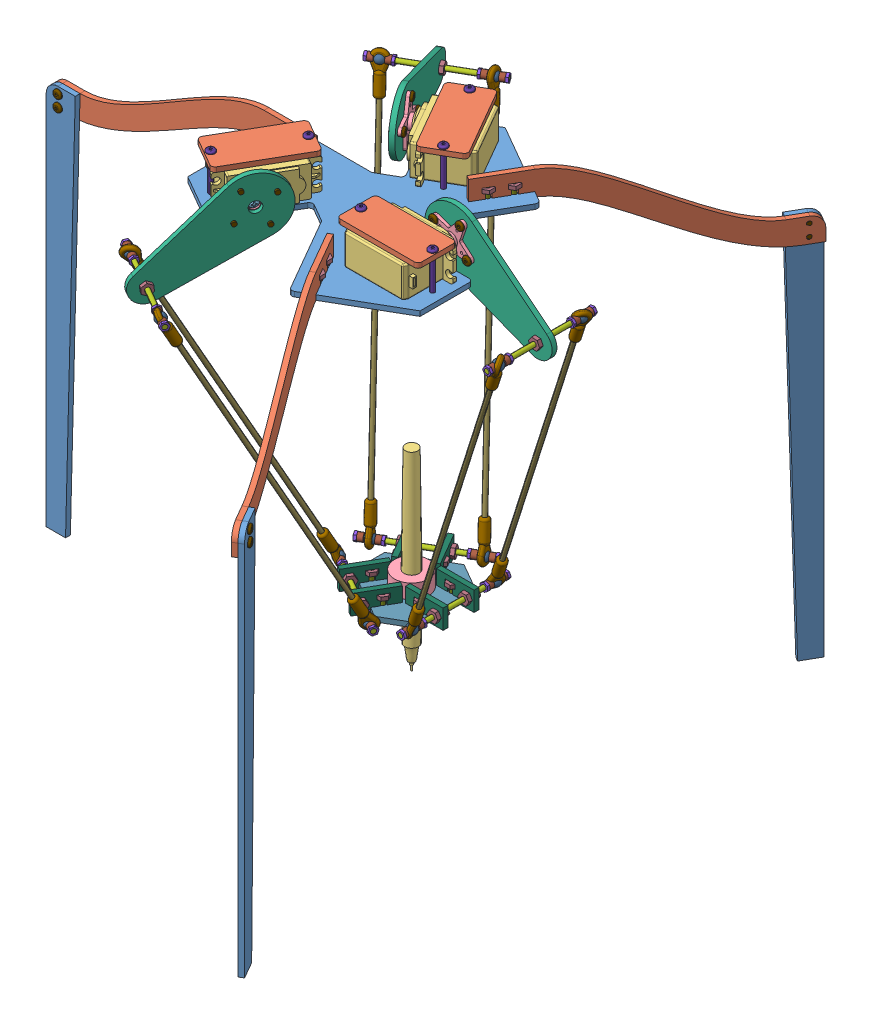
SolidWorks assembly robot, configuration Default. Lengths in mm.
Overall size (365.26 329.14 379.37).
210 component instances, 22 part files, 62 mates.
Components (placement in the parent):
- baseplate-1: baseplate [Default] at (-19.0722 -16.3081 15.1516) size (152.4 3.17 162.44)
- servo_cover-1: servo_cover [Default] at (26.6732 7.1869 43.9806) x (-1 0 0) z (0 1 0) size (53.34 25.4 3.17)
- servo_cover-2: servo_cover [Default] at (-16.9782 7.1869 -38.8796) x (0.5 0 0.866025) z (0 1 0) size (53.34 25.4 3.17)
- servo_cover-3: servo_cover [Default] at (-66.9115 7.1869 40.3538) x (0.5 0 -0.866025) z (0 1 0) size (53.34 25.4 3.17)
- servo_with_horn-2: servo_with_horn [Default] at (36.0362 17.1457 40.3908) x (0 1 0) z (-1 0 0) size (41.36 43.65 57.48) (flexible)
  - servo-1: servo [Default] at (-20.1188 -18.8299 -0.7716) size (20.32 41.27 53.29)
  - servohorn3-1: servohorn3 [Default] at (-20.1188 21.6577 -0.7716) x (-0.497836 0 -0.867271) z (0.867271 0 -0.497836) size (30.16 4.83 30.16)
  - #4 Screw-1: #4 Screw [90935A131] at (-20.1188 22.8928 -0.7716) x (1 0 0) z (0 1 0) size (5.56 5.56 8.28)
- arm-1: arm [Default] at (62.5908 -31.1625 3.6686) x (-0.865779 0.500426 0) z (0.500426 0.865779 0) size (152 113.14 262.73) (flexible)
  - upperarm-1: upperarm [Default] at (36.4291 9.905 11.5033) size (92.08 3.17 38.1)
  - elbow-1: elbow [Default] at (-23.4829 2.1195 2.2326) x (0.694665 0 -0.719334) z (0.719334 0 0.694665) size (27.1 71.7 23.49) (flexible)
    - elbow_rod-1: elbow_rod [Default] at (-9.1612 -25.5522 3.8591) size (2.95 69.85 2.95)
    - 4-40_nut-2: 4-40_nut [Default] at (-9.1612 42.7103 3.8591) x (-0.962597 0 -0.270938) z (0.270938 0 -0.962597) size (5.5 1.59 4.76)
    - balljoint-1: balljoint [Default] at (0.1328 32.669 -5.247) x (0.633314 -0.168787 -0.755264) z (-0.304454 0.842893 -0.443665) size (25.24 10.31 10.32) (flexible)
      - balljoint_joint-1: balljoint_joint [Default] at (-6.0674 0.1484 2.2064) size (25.24 5.95 10.32)
      - balljoint_ball-2: balljoint_ball [Default] at (-13.4478 0.1484 2.2064) x (-0.92173 -0.221131 -0.318613) z (-0.349176 0.830698 0.433609) size (6.35 5.63 6.35)
    - 4-40_spacer-1: 4-40_spacer [Default] at (-9.1612 39.5353 3.8591) x (0.693147 0 0.720796) z (-0.720796 0 0.693147) size (4.76 3.17 4.76)
    - 4-40_spacer-2: 4-40_spacer [Default] at (-9.1612 30.7353 3.8591) x (-0.319692 0 -0.947521) z (0.947521 0 -0.319692) size (4.76 3.17 4.76)
    - 4-40_spacer-4: 4-40_spacer [Default] at (-9.1612 -23.9647 3.8591) x (-0.98043 0 -0.196869) z (0.196869 0 -0.98043) size (4.76 3.17 4.76)
    - 4-40_spacer-5: 4-40_spacer [Default] at (-9.1612 -15.1646 3.8591) x (-0.915068 0 -0.403299) z (0.403299 0 -0.915068) size (4.76 3.17 4.76)
    - 4-40_nut-4: 4-40_nut [Default] at (-9.1612 -25.5522 3.8591) x (-0.98043 0 -0.196869) z (0.196869 0 -0.98043) size (5.5 1.59 4.76)
    - balljoint-2: balljoint [Default] at (0.3468 -18.3108 -5.8989) x (0.633314 -0.168787 -0.755264) z (-0.4896 -0.843183 -0.222111) size (25.24 10.26 10.32) (flexible)
      - balljoint_joint-1: balljoint_joint [Default] at (-6.0674 0.1484 2.2064) size (25.24 5.95 10.32)
      - balljoint_ball-2: balljoint_ball [Default] at (-13.4478 0.1484 2.2064) x (-0.6367 -0.596561 0.488598) z (0.752412 -0.619324 0.224308) size (6.35 5.63 6.35)
    - 4-40_nut-5: 4-40_nut [Default] at (-9.1612 29.1478 3.8591) x (0.327031 0 0.945013) z (-0.945013 0 0.327031) size (5.5 1.59 4.76)
    - 4-40_nut-6: 4-40_nut [Default] at (-9.1612 -11.9896 3.8591) x (0.998976 0 0.045234) z (-0.045234 0 0.998976) size (5.5 1.59 4.76)
  - lower_arm-1: lower_arm [Default] at (-51.4751 -1.0152 -219.9664) x (-0.230596 0.962712 -0.14146) z (0.967546 0.211415 -0.138414) size (2.79 228.6 2.79)
  - lower_arm-2: lower_arm [Default] at (-51.4751 -55.7152 -219.9664) x (-0.619276 -0.760264 0.196203) z (-0.778342 0.627303 -0.025956) size (2.79 228.6 2.79)
  - elbow-2: elbow [Default] at (-60.7209 -39.0108 -222.1485) x (-0.988334 0 0.152305) z (-0.152305 0 -0.988334) size (16.08 71.64 27.75) (flexible)
    - elbow_rod-1: elbow_rod [Default] at (-9.1612 -25.5522 3.8591) size (2.95 69.85 2.95)
    - 4-40_nut-2: 4-40_nut [Default] at (-9.1612 42.7103 3.8591) x (0.982806 0 -0.184641) z (0.184641 0 0.982806) size (5.5 1.59 4.76)
    - balljoint-1: balljoint [Default] at (-7.9824 41.1005 -8.9931) x (0.047152 0.168787 -0.984524) z (-0.310728 -0.934241 -0.175048) size (25.24 10.33 10.32) (flexible)
      - balljoint_joint-1: balljoint_joint [Default] at (-6.0674 0.1484 2.2064) size (25.24 5.95 10.32)
      - balljoint_ball-2: balljoint_ball [Default] at (-13.4478 0.1484 2.2064) x (-0.643697 -0.752934 0.136907) z (0.746435 -0.57826 0.329318) size (6.35 5.63 6.35)
    - 4-40_spacer-1: 4-40_spacer [Default] at (-9.1612 39.5353 3.8591) x (0.928598 0 0.371087) z (-0.371087 0 0.928598) size (4.76 3.17 4.76)
    - 4-40_spacer-2: 4-40_spacer [Default] at (-9.1612 30.7353 3.8591) x (-0.896981 0 0.442068) z (-0.442068 0 -0.896981) size (4.76 3.17 4.76)
    - 4-40_spacer-4: 4-40_spacer [Default] at (-9.1612 -23.9647 3.8591) x (-0.607719 0 -0.794152) z (0.794152 0 -0.607719) size (4.76 3.17 4.76)
    - 4-40_spacer-5: 4-40_spacer [Default] at (-9.1612 -15.1646 3.8591) x (0.496208 0 -0.868204) z (0.868204 0 0.496208) size (4.76 3.17 4.76)
    - 4-40_nut-4: 4-40_nut [Default] at (-9.1612 -25.5522 3.8591) x (0.965897 0 -0.258927) z (0.258927 0 0.965897) size (5.5 1.59 4.76)
    - balljoint-2: balljoint [Default] at (-7.7302 -17.7465 -9.692) x (0.047152 0.168787 -0.984524) z (-0.297051 0.943399 0.14751) size (25.24 9.83 10.32) (flexible)
      - balljoint_joint-1: balljoint_joint [Default] at (-6.0674 0.1484 2.2064) size (25.24 5.95 10.32)
      - balljoint_ball-2: balljoint_ball [Default] at (-13.4478 0.1484 2.2064) x (-0.644652 0.692059 0.324773) z (0.74561 0.662982 0.067237) size (6.35 5.63 6.35)
    - 4-40_nut-5: 4-40_nut [Default] at (-9.1612 29.1478 3.8591) x (0.327031 0 0.945013) z (-0.945013 0 0.327031) size (5.5 1.59 4.76)
    - 4-40_nut-6: 4-40_nut [Default] at (-9.1612 -11.9896 3.8591) x (0.998976 0 0.045234) z (-0.045234 0 0.998976) size (5.5 1.59 4.76)
  - 4-40_nut_wide-1: 4-40_nut_wide [Default] at (-27.0709 15.4613 11.5033) x (-0.82771 0 -0.561156) z (-0.561156 0 0.82771) size (7.33 2.38 6.35)
  - 4-40_nut_wide-2: 4-40_nut_wide [Default] at (-27.0709 7.5238 11.5033) x (0.999854 0 0.017072) z (-0.017072 0 0.999854) size (7.33 2.38 6.35)
- servo_with_horn-5: servo_with_horn [Default] at (-68.4841 17.1457 50.2573) x (0 1 0) z (0.5 0 -0.866025) size (41.99 43.65 57.8) (flexible)
  - servo-1: servo [Default] at (-20.1188 -18.8299 -0.7716) size (20.32 41.27 53.29)
  - servohorn3-1: servohorn3 [Default] at (-20.1188 21.6577 -0.7716) x (0.827646 0 -0.56125) z (0.56125 0 0.827646) size (30.16 4.83 30.16)
  - #4 Screw-1: #4 Screw [90935A131] at (-20.1188 22.8928 -0.7716) x (1 0 0) z (0 1 0) size (5.56 5.56 8.28)
- servo_with_horn-6: servo_with_horn [Default] at (-24.7686 17.1457 -45.1932) x (0 1 0) z (0.5 0 0.866025) size (36.75 43.65 55.18) (flexible)
  - servo-1: servo [Default] at (-20.1188 -18.8299 -0.7716) size (20.32 41.27 53.29)
  - servohorn3-1: servohorn3 [Default] at (-20.1188 21.6577 -0.7716) x (-0.191432 0 -0.981506) z (0.981506 0 -0.191432) size (30.16 4.83 30.16)
  - #4 Screw-1: #4 Screw [90935A131] at (-20.1188 22.8928 -0.7716) x (1 0 0) z (0 1 0) size (5.56 5.56 8.28)
- arm-4: arm [Default] at (-48.8699 -33.0103 89.7287) x (0.412983 0.563721 -0.715307) z (-0.281861 0.825965 0.488197) size (152.59 104.09 264.5) (flexible)
  - upperarm-1: upperarm [Default] at (36.4291 9.905 11.5033) size (92.08 3.17 38.1)
  - elbow-1: elbow [Default] at (-26.9301 2.1195 1.5635) x (0.401226 0 -0.915979) z (0.915979 0 0.401226) size (27.18 70.02 18.21) (flexible)
    - elbow_rod-1: elbow_rod [Default] at (-9.1612 -25.5522 3.8591) size (2.95 69.85 2.95)
    - 4-40_nut-2: 4-40_nut [Default] at (-9.1612 42.7103 3.8591) x (0.771228 0 0.636559) z (-0.636559 0 0.771228) size (5.5 1.59 4.76)
    - balljoint-1: balljoint [Default] at (3.4055 37.7799 -1.3074) x (0.848208 0.135879 -0.511938) z (-0.518583 0.409713 -0.750471) size (25.24 9.15 10.32) (flexible)
      - balljoint_joint-1: balljoint_joint [Default] at (-6.0674 0.1484 2.2064) size (25.24 5.95 10.32)
      - balljoint_ball-2: balljoint_ball [Default] at (-13.4478 0.1484 2.2064) x (0.953113 0.231885 0.194432) z (0.270392 -0.364083 -0.891253) size (6.35 5.63 6.35)
    - 4-40_spacer-1: 4-40_spacer [Default] at (-9.1612 39.5353 3.8591) x (-0.343072 0 -0.939309) z (0.939309 0 -0.343072) size (4.76 3.17 4.76)
    - 4-40_spacer-2: 4-40_spacer [Default] at (-9.1612 30.7353 3.8591) x (-0.090134 0 0.99593) z (-0.99593 0 -0.090134) size (4.76 3.17 4.76)
    - 4-40_spacer-4: 4-40_spacer [Default] at (-9.1612 -23.9647 3.8591) x (0.817451 0 0.575998) z (-0.575998 0 0.817451) size (4.76 3.17 4.76)
    - 4-40_spacer-5: 4-40_spacer [Default] at (-9.1612 -15.1646 3.8591) x (0.6743 0 0.738458) z (-0.738458 0 0.6743) size (4.76 3.17 4.76)
    - 4-40_nut-4: 4-40_nut [Default] at (-9.1612 -25.5522 3.8591) x (0.817451 0 0.575998) z (-0.575998 0 0.817451) size (5.5 1.59 4.76)
    - balljoint-2: balljoint [Default] at (2.47 -18.3399 -3.2343) x (0.848208 0.135879 -0.511938) z (-0.066506 0.986207 0.151568) size (25.24 9.61 10.32) (flexible)
      - balljoint_joint-1: balljoint_joint [Default] at (-6.0674 0.1484 2.2064) size (25.24 5.95 10.32)
      - balljoint_ball-2: balljoint_ball [Default] at (-13.4478 0.1484 2.2064) x (0.572901 -0.819625 -0.000384) z (-0.808283 -0.565051 0.165517) size (6.35 5.63 6.35)
    - 4-40_nut-5: 4-40_nut [Default] at (-9.1612 29.1478 3.8591) x (0.327031 0 0.945013) z (-0.945013 0 0.327031) size (5.5 1.59 4.76)
    - 4-40_nut-6: 4-40_nut [Default] at (-9.1612 -11.9896 3.8591) x (0.998976 0 0.045234) z (-0.045234 0 0.998976) size (5.5 1.59 4.76)
  - lower_arm-1: lower_arm [Default] at (-57.439 70.9288 -220.4679) x (-0.737442 -0.675404 0.003118) z (-0.663055 0.724822 0.187061) size (2.79 228.6 2.79)
  - lower_arm-2: lower_arm [Default] at (-57.439 16.2288 -220.4679) x (-0.086585 -0.988324 -0.125371) z (-0.987909 0.068933 0.138865) size (2.79 228.6 2.79)
  - elbow-2: elbow [Default] at (-49.5976 35.2306 -232.4779) x (0.996584 0 -0.082591) z (0.082591 0 0.996584) size (17.13 70.14 27.46) (flexible)
    - elbow_rod-1: elbow_rod [Default] at (-9.1612 -25.5522 3.8591) size (2.95 69.85 2.95)
    - 4-40_nut-2: 4-40_nut [Default] at (-9.1612 42.7103 3.8591) x (0.982333 0 -0.187143) z (0.187143 0 0.982333) size (5.5 1.59 4.76)
    - balljoint-1: balljoint [Default] at (-7.5187 36.8504 17.3875) x (0.04703 -0.135879 0.989609) z (-0.396092 -0.912025 -0.106403) size (25.24 10.51 10.32) (flexible)
      - balljoint_joint-1: balljoint_joint [Default] at (-6.0674 0.1484 2.2064) size (25.24 5.95 10.32)
      - balljoint_ball-2: balljoint_ball [Default] at (-13.4478 0.1484 2.2064) x (0.574702 0.780639 0.245602) z (-0.807003 0.490771 0.328466) size (6.35 5.63 6.35)
    - 4-40_spacer-1: 4-40_spacer [Default] at (-9.1612 39.5353 3.8591) x (0.92954 0 0.368721) z (-0.368721 0 0.92954) size (4.76 3.17 4.76)
    - 4-40_spacer-2: 4-40_spacer [Default] at (-9.1612 30.7353 3.8591) x (-0.895853 0 0.444351) z (-0.444351 0 -0.895853) size (4.76 3.17 4.76)
    - 4-40_spacer-4: 4-40_spacer [Default] at (-9.1612 -23.9647 3.8591) x (-0.609739 0 -0.792602) z (0.792602 0 -0.609739) size (4.76 3.17 4.76)
    - 4-40_spacer-5: 4-40_spacer [Default] at (-9.1612 -15.1646 3.8591) x (0.493996 0 -0.869464) z (0.869464 0 0.493996) size (4.76 3.17 4.76)
    - 4-40_nut-4: 4-40_nut [Default] at (-9.1612 -25.5522 3.8591) x (0.965234 0 -0.261386) z (0.261386 0 0.965234) size (5.5 1.59 4.76)
    - balljoint-2: balljoint [Default] at (-10.424 -18.6911 17.4101) x (0.04703 -0.135879 0.989609) z (0.889518 -0.445051 -0.103381) size (25.24 9.07 10.57) (flexible)
      - balljoint_joint-1: balljoint_joint [Default] at (-6.0674 0.1484 2.2064) size (25.24 5.95 10.32)
      - balljoint_ball-2: balljoint_ball [Default] at (-13.4478 0.1484 2.2064) x (0.575735 0.295033 -0.762552) z (-0.806267 0.359846 -0.469515) size (6.35 5.63 6.35)
    - 4-40_nut-5: 4-40_nut [Default] at (-9.1612 29.1478 3.8591) x (0.327031 0 0.945013) z (-0.945013 0 0.327031) size (5.5 1.59 4.76)
    - 4-40_nut-6: 4-40_nut [Default] at (-9.1612 -11.9896 3.8591) x (0.998976 0 0.045234) z (-0.045234 0 0.998976) size (5.5 1.59 4.76)
  - 4-40_nut_wide-1: 4-40_nut_wide [Default] at (-27.0709 15.4613 11.5033) x (-0.830576 0 -0.556905) z (-0.556905 0 0.830576) size (7.33 2.38 6.35)
  - 4-40_nut_wide-2: 4-40_nut_wide [Default] at (-27.0709 7.5238 11.5033) x (0.999929 0 0.011945) z (-0.011945 0 0.999929) size (7.33 2.38 6.35)
- arm-5: arm [Default] at (-73.706 -21.3376 -56.511) x (0.490465 0.194365 0.84951) z (-0.097182 0.980929 -0.168325) size (152.71 78.88 264.12) (flexible)
  - upperarm-1: upperarm [Default] at (36.4291 9.905 11.5033) size (92.08 3.17 38.1)
  - elbow-1: elbow [Default] at (-34.7249 2.1195 5.1601) x (-0.461858 0 -0.886954) z (0.886954 0 -0.461858) size (26.53 69.85 25.43) (flexible)
    - elbow_rod-1: elbow_rod [Default] at (-9.1612 -25.5522 3.8591) size (2.95 69.85 2.95)
    - 4-40_nut-2: 4-40_nut [Default] at (-9.1612 42.7103 3.8591) x (0.901206 0 0.433391) z (-0.433391 0 0.901206) size (5.5 1.59 4.76)
    - balljoint-1: balljoint [Default] at (3.7419 37.6048 8.1563) x (0.885824 0.032796 0.462862) z (-0.438882 -0.264659 0.858684) size (25.24 7.66 10.32) (flexible)
      - balljoint_joint-1: balljoint_joint [Default] at (-6.0674 0.1484 2.2064) size (25.24 5.95 10.32)
      - balljoint_ball-2: balljoint_ball [Default] at (-13.4478 0.1484 2.2064) x (0.028042 -0.265585 -0.96368) z (0.999069 -0.024184 0.035736) size (6.35 5.63 6.35)
    - 4-40_spacer-1: 4-40_spacer [Default] at (-9.1612 39.5353 3.8591) x (-0.55799 0 -0.829847) z (0.829847 0 -0.55799) size (4.76 3.17 4.76)
    - 4-40_spacer-2: 4-40_spacer [Default] at (-9.1612 30.7353 3.8591) x (0.150941 0 0.988543) z (-0.988543 0 0.150941) size (4.76 3.17 4.76)
    - 4-40_spacer-4: 4-40_spacer [Default] at (-9.1612 -23.9647 3.8591) x (0.931585 0 0.363524) z (-0.363524 0 0.931585) size (4.76 3.17 4.76)
    - 4-40_spacer-5: 4-40_spacer [Default] at (-9.1612 -15.1646 3.8591) x (0.831495 0 0.555533) z (-0.555533 0 0.831495) size (4.76 3.17 4.76)
    - 4-40_nut-4: 4-40_nut [Default] at (-9.1612 -25.5522 3.8591) x (0.931585 0 0.363524) z (-0.363524 0 0.931585) size (5.5 1.59 4.76)
    - balljoint-2: balljoint [Default] at (2.6927 -19.7305 10.3509) x (0.885824 0.032796 0.462862) z (-0.004709 0.998083 -0.061709) size (25.24 9.01 10.32) (flexible)
      - balljoint_joint-1: balljoint_joint [Default] at (-6.0674 0.1484 2.2064) size (25.24 5.95 10.32)
      - balljoint_ball-2: balljoint_ball [Default] at (-13.4478 0.1484 2.2064) x (0.951176 0.308281 -0.015044) z (0.306901 -0.949846 -0.060032) size (6.35 5.63 6.35)
    - 4-40_nut-5: 4-40_nut [Default] at (-9.1612 29.1478 3.8591) x (0.327031 0 0.945013) z (-0.945013 0 0.327031) size (5.5 1.59 4.76)
    - 4-40_nut-6: 4-40_nut [Default] at (-9.1612 -11.9896 3.8591) x (0.998976 0 0.045234) z (-0.045234 0 0.998976) size (5.5 1.59 4.76)
  - lower_arm-1: lower_arm [Default] at (-26.7375 46.5868 -224.51) x (-0.946031 0.323943 0.009293) z (0.324073 0.945508 0.031484) size (2.79 228.6 2.79)
  - lower_arm-2: lower_arm [Default] at (-26.7375 -8.1131 -224.51) x (-0.912676 -0.40842 -0.014691) z (-0.408681 0.912205 0.029356) size (2.79 228.6 2.79)
  - elbow-2: elbow [Default] at (-36.6397 10.1113 -231.3019) x (-0.948064 0 -0.318079) z (0.318079 0 -0.948064) size (13.16 69.85 26.08) (flexible)
    - elbow_rod-1: elbow_rod [Default] at (-9.1612 -25.5522 3.8591) size (2.95 69.85 2.95)
    - 4-40_nut-2: 4-40_nut [Default] at (-9.1612 42.7103 3.8591) x (0.171643 0 0.985159) z (-0.985159 0 0.171643) size (5.5 1.59 4.76)
    - balljoint-1: balljoint [Default] at (-15.4085 35.6062 -8.2015) x (-0.316569 -0.032796 -0.948002) z (0.918033 0.240947 -0.314897) size (25.24 7.7 10.32) (flexible)
      - balljoint_joint-1: balljoint_joint [Default] at (-6.0674 0.1484 2.2064) size (25.24 5.95 10.32)
      - balljoint_ball-2: balljoint_ball [Default] at (-13.4478 0.1484 2.2064) x (0.946092 0.107855 -0.305415) z (0.322235 -0.217942 0.921231) size (6.35 5.63 6.35)
    - 4-40_spacer-1: 4-40_spacer [Default] at (-9.1612 39.5353 3.8591) x (-0.383321 0 0.923615) z (-0.923615 0 -0.383321) size (4.76 3.17 4.76)
    - 4-40_spacer-2: 4-40_spacer [Default] at (-9.1612 30.7353 3.8591) x (-0.430181 0 -0.902743) z (0.902743 0 -0.430181) size (4.76 3.17 4.76)
    - 4-40_spacer-4: 4-40_spacer [Default] at (-9.1612 -23.9647 3.8591) x (0.80211 0 -0.597176) z (0.597176 0 0.80211) size (4.76 3.17 4.76)
    - 4-40_spacer-5: 4-40_spacer [Default] at (-9.1612 -15.1646 3.8591) x (0.861573 0 0.507633) z (-0.507633 0 0.861573) size (4.76 3.17 4.76)
    - 4-40_nut-4: 4-40_nut [Default] at (-9.1612 -25.5522 3.8591) x (0.246146 0 0.969233) z (-0.969233 0 0.246146) size (5.5 1.59 4.76)
    - balljoint-2: balljoint [Default] at (-15.5045 -18.625 -8.1856) x (-0.316569 -0.032796 -0.948002) z (0.947902 0.026543 -0.317453) size (25.24 6 10.32) (flexible)
      - balljoint_joint-1: balljoint_joint [Default] at (-6.0674 0.1484 2.2064) size (25.24 5.95 10.32)
      - balljoint_ball-2: balljoint_ball [Default] at (-13.4478 0.1484 2.2064) x (0.945678 0.039615 -0.322681) z (0.323445 -0.014518 0.946135) size (6.35 5.63 6.35)
    - 4-40_nut-5: 4-40_nut [Default] at (-9.1612 29.1478 3.8591) x (0.327031 0 0.945013) z (-0.945013 0 0.327031) size (5.5 1.59 4.76)
    - 4-40_nut-6: 4-40_nut [Default] at (-9.1612 -11.9896 3.8591) x (0.998976 0 0.045234) z (-0.045234 0 0.998976) size (5.5 1.59 4.76)
  - 4-40_nut_wide-1: 4-40_nut_wide [Default] at (-27.0709 15.4613 11.5033) x (-0.802812 0 -0.596233) z (-0.596233 0 0.802812) size (7.33 2.38 6.35)
  - 4-40_nut_wide-2: 4-40_nut_wide [Default] at (-27.0709 7.5238 11.5033) x (0.998195 0 0.060055) z (-0.060055 0 0.998195) size (7.33 2.38 6.35)
- hand-1: hand [Default] at (-35.5542 -256.4649 -27.669) size (60.32 14.2 67.85)
  - hand_base-1: hand_base [Default] at (1.9794 -4.0388 1.6994) size (50.8 3.17 58.66)
  - wrist_connector-2: wrist_connector [Default] at (29.61 2.3112 11.8594) x (0 0 -1) z (1 0 0) size (3.17 12.7 24.77)
  - wrist_connector-6: wrist_connector [Default] at (-20.6348 2.3112 20.5483) x (0.866025 0 0.5) z (-0.5 0 0.866025) size (3.17 12.7 24.77)
  - wrist_connector-7: wrist_connector [Default] at (-3.0372 2.3112 -27.3094) x (-0.866025 0 0.5) z (-0.5 0 -0.866025) size (3.17 12.7 24.77)
  - 4-40_38_screw-3: 4-40_38_screw [Default] at (18.4975 5.4862 11.8594) x (-0.241512 0 0.970398) z (0.970398 0 0.241512) size (5.41 11.02 5.41)
  - 4-40_nut_wide-1: 4-40_nut_wide [Default] at (18.4975 2.8192 11.8594) size (7.33 2.38 6.35)
  - 4-40_nut_wide-4: 4-40_nut_wide [Default] at (-15.0785 2.8192 10.9246) x (-0.5 0 0.866025) z (-0.866025 0 -0.5) size (7.33 2.38 6.35)
  - 4-40_nut_wide-5: 4-40_nut_wide [Default] at (2.5191 2.8192 -17.6857) x (-0.5 0 -0.866025) z (0.866025 0 -0.5) size (7.33 2.38 6.35)
  - 4-40_38_screw-4: 4-40_38_screw [Default] at (-15.0785 5.4862 10.9246) x (-0.719633 0 -0.694354) z (-0.694354 0 0.719633) size (5.41 11.02 5.41)
  - 4-40_38_screw-5: 4-40_38_screw [Default] at (2.5191 5.4862 -17.6857) x (0.961145 0 -0.276044) z (-0.276044 0 -0.961145) size (5.41 11.02 5.41)
  - 4-40_38_screw-8: 4-40_38_screw [Default] at (18.4975 5.4862 -8.4606) x (-0.241512 0 0.970398) z (0.970398 0 0.241512) size (5.41 11.02 5.41)
  - 4-40_nut_wide-8: 4-40_nut_wide [Default] at (18.4975 2.8192 -8.4606) size (7.33 2.38 6.35)
  - wrist_connector-11: wrist_connector [Default] at (29.61 2.3112 -8.4606) x (0 0 -1) z (1 0 0) size (3.17 12.7 24.77)
  - wrist_connector-12: wrist_connector [Default] at (-3.0372 2.3112 30.7083) x (0.866025 0 0.5) z (-0.5 0 0.866025) size (3.17 12.7 24.77)
  - wrist_connector-13: wrist_connector [Default] at (-20.6348 2.3112 -17.1494) x (-0.866025 0 0.5) z (-0.5 0 -0.866025) size (3.17 12.7 24.77)
  - 4-40_nut_wide-9: 4-40_nut_wide [Default] at (2.5191 2.8192 21.0846) x (-0.5 0 0.866025) z (-0.866025 0 -0.5) size (7.33 2.38 6.35)
  - 4-40_nut_wide-10: 4-40_nut_wide [Default] at (-15.0785 2.8192 -7.5257) x (-0.5 0 -0.866025) z (0.866025 0 -0.5) size (7.33 2.38 6.35)
  - 4-40_38_screw-9: 4-40_38_screw [Default] at (2.5191 5.4862 21.0846) x (-0.719633 0 -0.694354) z (-0.694354 0 0.719633) size (5.41 11.02 5.41)
  - 4-40_38_screw-10: 4-40_38_screw [Default] at (-15.0785 5.4862 -7.5257) x (0.961145 0 -0.276044) z (-0.276044 0 -0.961145) size (5.41 11.02 5.41)
- 4-40_125_screw-1: 4-40_125_screw [Default] at (50.1682 -21.3881 43.9806) size (5.41 33.25 5.41)
- 4-40_125_screw-6: 4-40_125_screw [Default] at (-78.659 -21.3881 60.7011) x (-0.5 0 0.866025) z (-0.866025 0 -0.5) size (5.41 33.25 5.41)
- 4-40_125_screw-5: 4-40_125_screw [Default] at (-28.7257 -21.3881 -59.2268) x (-0.5 0 -0.866025) z (0.866025 0 -0.5) size (5.41 33.25 5.41)
- 4-40_125_screw-2: 4-40_125_screw [Default] at (3.1782 -21.3881 43.9806) size (5.41 33.25 5.41)
- 4-40_125_screw-4: 4-40_125_screw [Default] at (-55.164 -21.3881 20.0065) x (-0.5 0 0.866025) z (-0.866025 0 -0.5) size (5.41 33.25 5.41)
- 4-40_125_screw-3: 4-40_125_screw [Default] at (-5.2307 -21.3881 -18.5323) x (-0.5 0 -0.866025) z (0.866025 0 -0.5) size (5.41 33.25 5.41)
- 4-40_nut_wide-17: 4-40_nut_wide [Default] at (-5.9442 -254.1537 -17.3971) x (0.5 0.866025 0) z (-0.866025 0.5 0) size (7.33 2.38 6.35)
- 4-40_nut_wide-18: 4-40_nut_wide [Default] at (-5.9442 -254.1537 -11.8408) x (0.5 0.866025 0) z (-0.866025 0.5 0) size (7.33 2.38 6.35)
- 4-40_14_screw-1: 4-40_14_screw [Default] at (43.1632 8.0223 12.383) x (-0.533794 -0.845615 0) z (-0.845615 0.533794 0) size (5.41 7.85 5.41)
- 4-40_14_screw-5: 4-40_14_screw [Default] at (-48.1941 7.5166 71.1295) x (0.25 0.866025 -0.433013) z (-0.433013 0.5 0.75) size (5.41 7.85 5.41)
- 4-40_14_screw-6: 4-40_14_screw [Default] at (-50.6441 9.4847 -33.9953) x (-0.430563 0.50839 -0.745758) z (-0.254195 -0.861127 -0.440279) size (5.41 7.85 5.41)
- 4-40_38_screw-2: 4-40_38_screw [Default] at (1.3162 -6.7831 65.7053) x (0.682996 0 0.730423) z (0.730423 0 -0.682996) size (5.41 11.02 5.41)
- 4-40_38_screw-3: 4-40_38_screw [Default] at (7.6662 -6.7831 76.7039) x (0.928001 0 0.372577) z (0.372577 0 -0.928001) size (5.41 11.02 5.41)
- 4-40_nut_wide-19: 4-40_nut_wide [Default] at (-54.8141 -254.1537 -6.327) x (-0.25 0.866025 0.433013) z (0.433013 0.5 -0.75) size (7.33 2.38 6.35)
- 4-40_nut_wide-20: 4-40_nut_wide [Default] at (-39.9661 -254.1537 -54.1846) x (-0.25 0.866025 -0.433013) z (0.433013 0.5 0.75) size (7.33 2.38 6.35)
- 4-40_nut_wide-21: 4-40_nut_wide [Default] at (-59.626 -254.1537 -9.1051) x (-0.25 0.866025 0.433013) z (0.433013 0.5 -0.75) size (7.33 2.38 6.35)
- 4-40_nut_wide-22: 4-40_nut_wide [Default] at (-35.1543 -254.1537 -56.9628) x (-0.25 0.866025 -0.433013) z (0.433013 0.5 0.75) size (7.33 2.38 6.35)
- 4-40_14_screw-2: 4-40_14_screw [Default] at (47.8032 -9.3285 12.383) x (-0.845615 0.533794 0) z (0.533794 0.845615 0) size (5.41 7.85 5.41)
- 4-40_14_screw-3: 4-40_14_screw [Default] at (30.4524 -13.9685 12.383) x (0.533794 0.845615 0) z (0.845615 -0.533794 0) size (5.41 7.85 5.41)
- 4-40_14_screw-4: 4-40_14_screw [Default] at (25.8124 3.3823 12.383) x (0.845615 -0.533794 0) z (-0.533794 -0.845615 0) size (5.41 7.85 5.41)
- 4-40_14_screw-7: 4-40_14_screw [Default] at (-55.6388 -5.4416 -42.6464) x (-0.254195 -0.861127 -0.440279) z (0.430563 -0.50839 0.745758) size (5.41 7.85 5.41)
- 4-40_14_screw-8: 4-40_14_screw [Default] at (-48.1756 -15.4309 -29.7199) x (0.430563 -0.50839 0.745758) z (0.254195 0.861127 0.440279) size (5.41 7.85 5.41)
- 4-40_14_screw-9: 4-40_14_screw [Default] at (-43.181 -0.5047 -21.0688) x (0.254195 0.861127 0.440279) z (-0.430563 0.50839 -0.745758) size (5.41 7.85 5.41)
- 4-40_14_screw-10: 4-40_14_screw [Default] at (-49.8594 -10.1324 74.0138) x (-0.433013 0.5 0.75) z (-0.25 -0.866025 0.433013) size (5.41 7.85 5.41)
- 4-40_14_screw-11: 4-40_14_screw [Default] at (-41.0349 -13.4629 58.7293) x (-0.25 -0.866025 0.433013) z (0.433013 -0.5 -0.75) size (5.41 7.85 5.41)
- 4-40_14_screw-12: 4-40_14_screw [Default] at (-39.3696 4.1861 55.845) x (0.433013 -0.5 -0.75) z (0.25 0.866025 -0.433013) size (5.41 7.85 5.41)
- support-1: support [Default] at (55.7452 -80.6551 165.2482) x (-0.5 0 -0.866025) z (0.866025 0 -0.5) size (171.45 304.8 10.84)
  - support_lower-1: support_lower [Default] at (-40.5663 25.2945 4.2216) size (19.05 254 3.17)
  - support_upper-1: support_upper [Default] at (91.1962 64.347 1.0466) size (171.45 66.67 3.17)
  - 4-40_14_screw-1: 4-40_14_screw [Default] at (-40.5663 17.6745 1.0466) x (-0.100905 0.994896 0) z (0.994896 0.100905 0) size (5.41 7.85 5.41)
  - 4-40_14_screw-2: 4-40_14_screw [Default] at (-40.5663 25.2945 1.0466) x (0.562879 0.826539 0) z (0.826539 -0.562879 0) size (5.41 7.85 5.41)
  - 4-40_nut_wide-1: 4-40_nut_wide [Default] at (100.7212 71.205 2.6345) x (0.866025 0 0.5) z (-0.5 0 0.866025) size (7.33 2.38 6.35)
  - 4-40_nut_wide-2: 4-40_nut_wide [Default] at (113.4212 71.205 2.6345) x (0.866025 0 0.5) z (-0.5 0 0.866025) size (7.33 2.38 6.35)
- 4-40_38_screw-4: 4-40_38_screw [Default] at (20.8644 -6.7831 -38.7806) x (-0.141339 0 -0.989961) z (-0.989961 0 0.141339) size (5.41 11.02 5.41)
- 4-40_38_screw-5: 4-40_38_screw [Default] at (-85.7472 -6.7831 7.5316) x (-0.786662 0 0.617384) z (0.617384 0 0.786662) size (5.41 11.02 5.41)
- 4-40_38_screw-6: 4-40_38_screw [Default] at (14.5144 -6.7831 -27.7821) x (0.291067 0 -0.956703) z (-0.956703 0 -0.291067) size (5.41 11.02 5.41)
- 4-40_38_screw-7: 4-40_38_screw [Default] at (-73.0472 -6.7831 7.5316) x (-0.974062 0 0.22628) z (0.22628 0 0.974062) size (5.41 11.02 5.41)
- support-2: support [Default] at (73.5066 -80.6551 -124.6905) x (-0.5 0 0.866025) z (-0.866025 0 -0.5) size (171.45 304.8 10.84)
  - support_lower-1: support_lower [Default] at (-40.5663 25.2945 4.2216) size (19.05 254 3.17)
  - support_upper-1: support_upper [Default] at (91.1962 64.347 1.0466) size (171.45 66.67 3.17)
  - 4-40_14_screw-1: 4-40_14_screw [Default] at (-40.5663 17.6745 1.0466) x (-0.100905 0.994896 0) z (0.994896 0.100905 0) size (5.41 7.85 5.41)
  - 4-40_14_screw-2: 4-40_14_screw [Default] at (-40.5663 25.2945 1.0466) x (0.562879 0.826539 0) z (0.826539 -0.562879 0) size (5.41 7.85 5.41)
  - 4-40_nut_wide-1: 4-40_nut_wide [Default] at (100.7212 71.205 2.6345) x (0.866025 0 0.5) z (-0.5 0 0.866025) size (7.33 2.38 6.35)
  - 4-40_nut_wide-2: 4-40_nut_wide [Default] at (113.4212 71.205 2.6345) x (0.866025 0 0.5) z (-0.5 0 0.866025) size (7.33 2.38 6.35)
- support-3: support [Default] at (-186.4684 -80.6551 4.8971) size (171.45 304.8 10.84)
  - support_lower-1: support_lower [Default] at (-40.5663 25.2945 4.2216) size (19.05 254 3.17)
  - support_upper-1: support_upper [Default] at (91.1962 64.347 1.0466) size (171.45 66.67 3.17)
  - 4-40_14_screw-1: 4-40_14_screw [Default] at (-40.5663 17.6745 1.0466) x (-0.100905 0.994896 0) z (0.994896 0.100905 0) size (5.41 7.85 5.41)
  - 4-40_14_screw-2: 4-40_14_screw [Default] at (-40.5663 25.2945 1.0466) x (0.562879 0.826539 0) z (0.826539 -0.562879 0) size (5.41 7.85 5.41)
  - 4-40_nut_wide-1: 4-40_nut_wide [Default] at (100.7212 71.205 2.6345) x (0.866025 0 0.5) z (-0.5 0 0.866025) size (7.33 2.38 6.35)
  - 4-40_nut_wide-2: 4-40_nut_wide [Default] at (113.4212 71.205 2.6345) x (0.866025 0 0.5) z (-0.5 0 0.866025) size (7.33 2.38 6.35)
- pen-1: pen [Default] at (-33.5748 -257.3287 -25.9696) x (0.561211 0 0.827673) z (-0.827673 0 0.561211) size (9.98 127.05 9.98)
- shaft_collar-1: shaft_collar [Default] at (-33.5748 -270.0287 -25.9696) x (0.977625 0 0.210355) z (-0.210355 0 0.977625) size (22.23 9.53 22.23)
- 4-40_nut_wide-23: 4-40_nut_wide [Default] at (-5.9442 -254.1537 -32.1608) x (1 0 0) z (0 1 0) size (7.33 2.38 6.35)
- 4-40_nut_wide-24: 4-40_nut_wide [Default] at (-5.9442 -254.1537 -37.7171) x (1 0 0) z (0 1 0) size (7.33 2.38 6.35)
- 4-40_nut_wide-25: 4-40_nut_wide [Default] at (-42.0283 -254.1537 1.0549) x (-0.5 0 0.866025) z (0 1 0) size (7.33 2.38 6.35)
- 4-40_nut_wide-26: 4-40_nut_wide [Default] at (-52.7519 -254.1537 -46.8028) x (-0.5 0 -0.866025) z (0 1 0) size (7.33 2.38 6.35)
- 4-40_nut_wide-27: 4-40_nut_wide [Default] at (-37.2165 -254.1537 3.833) x (-0.5 0 0.866025) z (0 1 0) size (7.33 2.38 6.35)
- 4-40_nut_wide-28: 4-40_nut_wide [Default] at (-57.5638 -254.1537 -44.0246) x (-0.5 0 -0.866025) z (0 1 0) size (7.33 2.38 6.35)
- shaft_collar-2: shaft_collar [Default] at (-33.5748 -257.3287 -25.9696) size (22.23 9.53 22.23)
Mates (geometry in assembly coordinates):
- Coincident24: coincident anti-aligned: plane of servo_cover-1 through (2.5432 10.3619 33.8206) normal (0 1 0); plane of 4-40_125_screw-1 through (50.1682 10.3619 43.9806) normal (0 -1 0)
- Concentric9: concentric aligned: cylinder of servo_cover-1 through (50.1682 10.3619 43.9806) axis (0 -1 0) radius 1.5875; cylinder of 4-40_125_screw-1 through (50.1682 10.3619 43.9806) axis (0 -1 0) radius 1.4224
- Concentric10: concentric aligned: cylinder of servo_cover-1 through (3.1782 10.3619 43.9806) axis (0 -1 0) radius 1.5875; cylinder of 4-40_125_screw-2 through (3.1782 10.3619 43.9806) axis (0 -1 0) radius 1.4224
- Coincident26: coincident anti-aligned: plane of servo_cover-1 through (2.5432 10.3619 33.8206) normal (0 1 0); plane of 4-40_125_screw-2 through (3.1782 10.3619 43.9806) normal (0 -1 0)
- Coincident30: coincident anti-aligned: plane of baseplate-1 through (31.826 -13.1331 -40.5061) normal (0 1 0); plane of servo_with_horn-2/servo-1 through (46.9678 -13.1331 33.8206) normal (0 -1 0)
- Coincident31: coincident aligned: plane of baseplate-1 through (8.8678 -13.1331 24.6131) normal (0 0 -1); plane of servo_with_horn-2/servo-1 through (14.7098 -2.9731 24.6131) normal (0 0 -1)
- Coincident32: coincident anti-aligned: plane of baseplate-1 through (6.3278 -13.1331 8.7381) normal (1 0 0); plane of servo_with_horn-2/servo-1 through (6.3278 -13.1331 33.8206) normal (-1 0 0)
- Coincident33: coincident anti-aligned: plane of servo_with_horn-2/servohorn3-1 through (30.4524 -13.9685 16.7486) normal (0 0 -1); plane of arm-1/upperarm-1 through (91.7848 -34.7502 16.7486) normal (0 0 1)
- Concentric13: concentric anti-aligned: circle of servo_with_horn-2/servohorn3-1; circle of arm-1/upperarm-1
- Concentric14: concentric anti-aligned: cylinder of servo_with_horn-2/servohorn3-1 through (47.8032 -9.3285 16.7486) axis (0 0 1) radius 0.7937; cylinder of arm-1/upperarm-1 through (47.8032 -9.3285 16.7486) axis (0 0 -1) radius 1.016
- Coincident34: coincident anti-aligned: plane of baseplate-1 through (31.826 -13.1331 -40.5061) normal (0 1 0); plane of servo_with_horn-5/servo-1 through (-68.26 -13.1331 63.0094) normal (0 -1 0)
- Coincident35: coincident aligned: plane of baseplate-1 through (-41.2361 -13.1331 34.6176) normal (0.866025 0 0.5); plane of servo_with_horn-5/servo-1 through (-44.1571 -2.9731 39.6769) normal (0.866025 0 0.5)
- Coincident36: coincident anti-aligned: plane of baseplate-1 through (-26.2278 -13.1331 40.3497) normal (-0.5 0 0.866025); plane of servo_with_horn-5/servo-1 through (-47.94 -13.1331 27.8142) normal (0.5 0 -0.866025)
- Concentric15: concentric anti-aligned: circle of servo_with_horn-5/servohorn3-1; circle of arm-4/upperarm-1
- Coincident37: coincident anti-aligned: plane of servo_with_horn-5/servohorn3-1 through (-53.6401 -10.1324 71.831) normal (0.866025 0 0.5); plane of arm-4/upperarm-1 through (-74.6196 -38.7694 108.1686) normal (-0.866025 0 -0.5)
- Concentric16: concentric anti-aligned: cylinder of servo_with_horn-5/servohorn3-1 through (-51.9749 7.5166 68.9467) axis (-0.866025 0 -0.5) radius 0.7937; cylinder of arm-4/upperarm-1 through (-51.9749 7.5166 68.9467) axis (0.866025 0 0.5) radius 1.016
- Coincident38: coincident anti-aligned: plane of baseplate-1 through (31.826 -13.1331 -40.5061) normal (0 1 0); plane of servo_with_horn-6/servo-1 through (-35.9244 -13.1331 -51.3752) normal (0 -1 0)
- Coincident39: coincident aligned: plane of baseplate-1 through (-24.8483 -13.1331 -13.7759) normal (-0.866025 0 0.5); plane of servo_with_horn-6/servo-1 through (-27.7693 -2.9731 -18.8352) normal (-0.866025 0 0.5)
- Coincident40: coincident anti-aligned: plane of baseplate-1 through (-37.3363 -13.1331 -3.633) normal (-0.5 0 -0.866025); plane of servo_with_horn-6/servo-1 through (-15.6044 -13.1331 -16.1799) normal (0.5 0 0.866025)
- Coincident41: coincident anti-aligned: plane of servo_with_horn-6/servohorn3-1 through (-44.3949 -15.4309 -31.9027) normal (-0.866025 0 0.5); plane of arm-5/upperarm-1 through (-76.7736 -15.3153 -87.9843) normal (0.866025 0 -0.5)
- Concentric17: concentric anti-aligned: circle of servo_with_horn-6/servohorn3-1; circle of arm-5/upperarm-1
- Concentric18: concentric anti-aligned: cylinder of servo_with_horn-6/servohorn3-1 through (-51.858 -5.4416 -44.8292) axis (0.866025 0 -0.5) radius 0.7937; cylinder of arm-5/upperarm-1 through (-51.858 -5.4416 -44.8292) axis (-0.866025 0 0.5) radius 1.016
- Concentric19: concentric aligned: cylinder of arm-1/elbow-2/elbow_rod-1 through (-5.9442 -254.1537 8.9557) axis (0 0 -1) radius 1.4732; circle of hand-1/wrist_connector-2
- Concentric20: concentric aligned: cylinder of arm-5/elbow-2/elbow_rod-1 through (-17.144 -254.1537 -67.361) axis (-0.866025 0 0.5) radius 1.4732; cylinder of hand-1/wrist_connector-7 through (-37.2165 -254.1537 -55.7721) axis (-0.866025 0 0.5) radius 1.5875
- Concentric21: concentric aligned: cylinder of arm-4/elbow-2/elbow_rod-1 through (-77.6363 -254.1537 -19.5033) axis (0.866025 0 0.5) radius 1.4732; cylinder of hand-1/wrist_connector-6 through (-57.5638 -254.1537 -7.9145) axis (0.866025 0 0.5) radius 1.5875
- Distance1: distance = 8.0277 mm anti-aligned: plane of arm-4/elbow-2/4-40_nut-5 through (-63.4703 -252.3684 -13.7394) normal (0.866025 0 0.5); plane of hand-1/wrist_connector-6 through (-59.945 -247.8037 -3.79) normal (-0.866025 0 -0.5)
- Distance3: distance = 8.0277 mm anti-aligned: plane of arm-1/elbow-2/4-40_nut-5 through (-3.6169 -255.618 -6.1944) normal (0 0 -1); plane of hand-1/wrist_connector-2 through (-1.1817 -247.8037 -14.2221) normal (0 0 1)
- Concentric22: concentric anti-aligned: cylinder of arm-1/elbow-2/elbow_rod-1 through (-5.9442 -254.1537 8.9557) axis (0 0 -1) radius 1.4732; cylinder of 4-40_nut_wide-17 through (-5.9442 -254.1537 -19.7783) axis (0 0 1) radius 1.4986
- Concentric23: concentric anti-aligned: cylinder of arm-1/elbow-2/elbow_rod-1 through (-5.9442 -254.1537 8.9557) axis (0 0 -1) radius 1.4732; cylinder of 4-40_nut_wide-18 through (-5.9442 -254.1537 -14.2221) axis (0 0 1) radius 1.4986
- Coincident42: coincident anti-aligned: plane of hand-1/wrist_connector-2 through (-1.1817 -247.8037 -17.3971) normal (0 0 -1); plane of 4-40_nut_wide-17 through (-2.278 -254.1537 -17.3971) normal (0 0 1)
- Coincident43: coincident anti-aligned: plane of hand-1/wrist_connector-2 through (-1.1817 -247.8037 -14.2221) normal (0 0 1); plane of 4-40_nut_wide-18 through (-2.278 -254.1537 -14.2221) normal (0 0 -1)
- Symmetric1: symmetric anti-aligned: plane of hand-1/wrist_connector-2 through (-1.1817 -260.5037 -14.2221) normal (0 -1 0); plane of 4-40_nut_wide-17 through (-2.278 -254.1537 -19.7783) normal (0.866025 -0.5 0); plane of 4-40_nut_wide-18 through (-7.7772 -257.3287 -14.2221) normal (-0.866025 -0.5 0)
- Concentric26: concentric aligned: cylinder of arm-1/upperarm-1 through (43.1632 8.0223 16.7486) axis (0 0 -1) radius 1.016; cylinder of 4-40_14_screw-1 through (43.1632 8.0223 18.733) axis (0 0 -1) radius 1.4224
- Coincident47: coincident anti-aligned: plane of servo_with_horn-2/servohorn3-1 through (30.4524 -13.9685 18.733) normal (0 0 1); plane of 4-40_14_screw-1 through (43.1632 8.0223 18.733) normal (0 0 -1)
- Coincident48: coincident anti-aligned: plane of servo_with_horn-6/servohorn3-1 through (-42.6764 -15.4309 -32.8949) normal (0.866025 0 -0.5); plane of 4-40_14_screw-6 through (-45.1448 9.4847 -37.1703) normal (-0.866025 0 0.5)
- Concentric28: concentric aligned: cylinder of arm-5/upperarm-1 through (-46.8633 9.4847 -36.1781) axis (-0.866025 0 0.5) radius 1.016; cylinder of 4-40_14_screw-6 through (-45.1448 9.4847 -37.1703) axis (-0.866025 0 0.5) radius 1.4224
- Coincident49: coincident anti-aligned: plane of servo_with_horn-5/servohorn3-1 through (-55.3586 -10.1324 70.8388) normal (-0.866025 0 -0.5); plane of 4-40_14_screw-5 through (-53.6934 7.5166 67.9545) normal (0.866025 0 0.5)
- Concentric29: concentric aligned: cylinder of arm-4/upperarm-1 through (-51.9749 7.5166 68.9467) axis (0.866025 0 0.5) radius 1.016; cylinder of 4-40_14_screw-5 through (-53.6934 7.5166 67.9545) axis (0.866025 0 0.5) radius 1.4224
- Concentric30: concentric anti-aligned: cylinder of baseplate-1 through (7.6662 -13.1331 76.7039) axis (0 -1 0) radius 1.5875; cylinder of 4-40_38_screw-3 through (7.6662 -16.3081 76.7039) axis (0 1 0) radius 1.4224
- Concentric31: concentric anti-aligned: cylinder of support-1/4-40_nut_wide-1 through (7.6662 -7.0689 76.7039) axis (0 -1 0) radius 1.4986; cylinder of 4-40_38_screw-3 through (7.6662 -16.3081 76.7039) axis (0 1 0) radius 1.4224
- Coincident56: coincident anti-aligned: plane of baseplate-1 through (31.826 -16.3081 -40.5061) normal (0 -1 0); plane of 4-40_38_screw-3 through (7.6662 -16.3081 76.7039) normal (0 1 0)
- Concentric32: concentric anti-aligned: cylinder of baseplate-1 through (1.3162 -13.1331 65.7053) axis (0 -1 0) radius 1.5875; cylinder of 4-40_38_screw-2 through (1.3162 -16.3081 65.7053) axis (0 1 0) radius 1.4224
- Concentric33: concentric anti-aligned: cylinder of support-1/4-40_nut_wide-2 through (1.3162 -7.0689 65.7053) axis (0 -1 0) radius 1.4986; cylinder of 4-40_38_screw-2 through (1.3162 -16.3081 65.7053) axis (0 1 0) radius 1.4224
- Coincident57: coincident anti-aligned: plane of baseplate-1 through (31.826 -16.3081 -40.5061) normal (0 -1 0); plane of 4-40_38_screw-2 through (1.3162 -16.3081 65.7053) normal (0 1 0)
- Concentric34: concentric anti-aligned: cylinder of hand-1/hand_base-1 through (-33.5748 -257.3287 -25.9696) axis (0 -1 0) radius 4.3656; cylinder of pen-1 through (-33.5748 -289.5232 -25.9696) axis (0 1 0) radius 4.5466
- Coincident58: coincident anti-aligned: plane of hand-1/hand_base-1 through (-10.7067 -257.3287 -45.0196) normal (0 1 0); plane of pen-1 through (-33.5748 -257.3287 -25.9696) normal (0 -1 0)
- Coincident59: coincident aligned: plane of support-2/support_lower-1 through (91.3529 -305.2331 -170.3943) normal (0 -1 0); circle of pen-1
- Concentric35: concentric anti-aligned: cylinder of pen-1 through (-33.5748 -289.5232 -25.9696) axis (0 1 0) radius 4.5466; cylinder of shaft_collar-1 through (-33.5748 -260.5037 -25.9696) axis (0 -1 0) radius 4.7625
- Coincident60: coincident anti-aligned: plane of hand-1/hand_base-1 through (-10.7067 -260.5037 -45.0196) normal (0 -1 0); plane of shaft_collar-1 through (-33.5748 -260.5037 -25.9696) normal (0 1 0)
- Coincident61: coincident anti-aligned: plane of baseplate-1 through (9.4664 -13.1331 82.9969) normal (0.5 0 0.866025); plane of support-1/support_upper-1 through (12.2156 -16.3081 81.4096) normal (-0.5 0 -0.866025)
- Coincident62: coincident anti-aligned: plane of baseplate-1 through (31.826 -13.1331 -40.5061) normal (0 1 0); plane of support-1/support_upper-1 through (8.2469 -13.1331 74.5355) normal (0 -1 0)
- Distance4: distance = 8.0277 mm anti-aligned: plane of hand-1/wrist_connector-7 through (-39.5977 -247.8037 -59.8966) normal (0.866025 0 -0.5); plane of arm-5/elbow-2/4-40_nut-5 through (-31.3072 -255.9455 -61.5922) normal (-0.866025 0 0.5)
- Concentric36: concentric anti-aligned: cylinder of arm-1/elbow-2/elbow_rod-1 through (-5.9442 -254.1537 8.9557) axis (0 0 -1) radius 1.4732; cylinder of 4-40_nut_wide-23 through (-5.9442 -254.1537 -34.5421) axis (0 0 1) radius 1.4986
- Concentric37: concentric anti-aligned: cylinder of arm-1/elbow-2/elbow_rod-1 through (-5.9442 -254.1537 8.9557) axis (0 0 -1) radius 1.4732; cylinder of 4-40_nut_wide-24 through (-5.9442 -254.1537 -40.0983) axis (0 0 1) radius 1.4986
- Coincident64: coincident anti-aligned: plane of hand-1/wrist_connector-11 through (-1.1817 -247.8037 -34.5421) normal (0 0 1); plane of 4-40_nut_wide-23 through (-4.1111 -257.3287 -34.5421) normal (0 0 -1)
- Coincident65: coincident anti-aligned: plane of hand-1/wrist_connector-11 through (-1.1817 -247.8037 -37.7171) normal (0 0 -1); plane of 4-40_nut_wide-24 through (-4.1111 -257.3287 -37.7171) normal (0 0 1)
- Concentric38: concentric anti-aligned: circle of pen-1; cylinder of shaft_collar-2 through (-33.5748 -247.8037 -25.9696) axis (0 -1 0) radius 4.7625
- Coincident66: coincident anti-aligned: plane of hand-1/hand_base-1 through (-10.7067 -257.3287 -45.0196) normal (0 1 0); plane of shaft_collar-2 through (-33.5748 -257.3287 -25.9696) normal (0 -1 0)
- center hand: unknown: cylinder of hand-1/hand_base-1 through (-17.9186 -234.0457 18.8024) axis (0 -1 0) radius 4.7625
- servo center 1: unknown: cylinder of arm-1/upperarm-1 through (36.8078 -2.9731 16.755) axis (0 0 -1) radius 3.556
- servo center 2: unknown: cylinder of arm-4/upperarm-1 through (-48.4007 -2.9731 62.7434) axis (0.866025 0 0.5) radius 3.556
- servo center 3: unknown: cylinder of arm-5/upperarm-1 through (-45.6236 -2.9731 -34.0436) axis (-0.866025 0 0.5) radius 3.556
